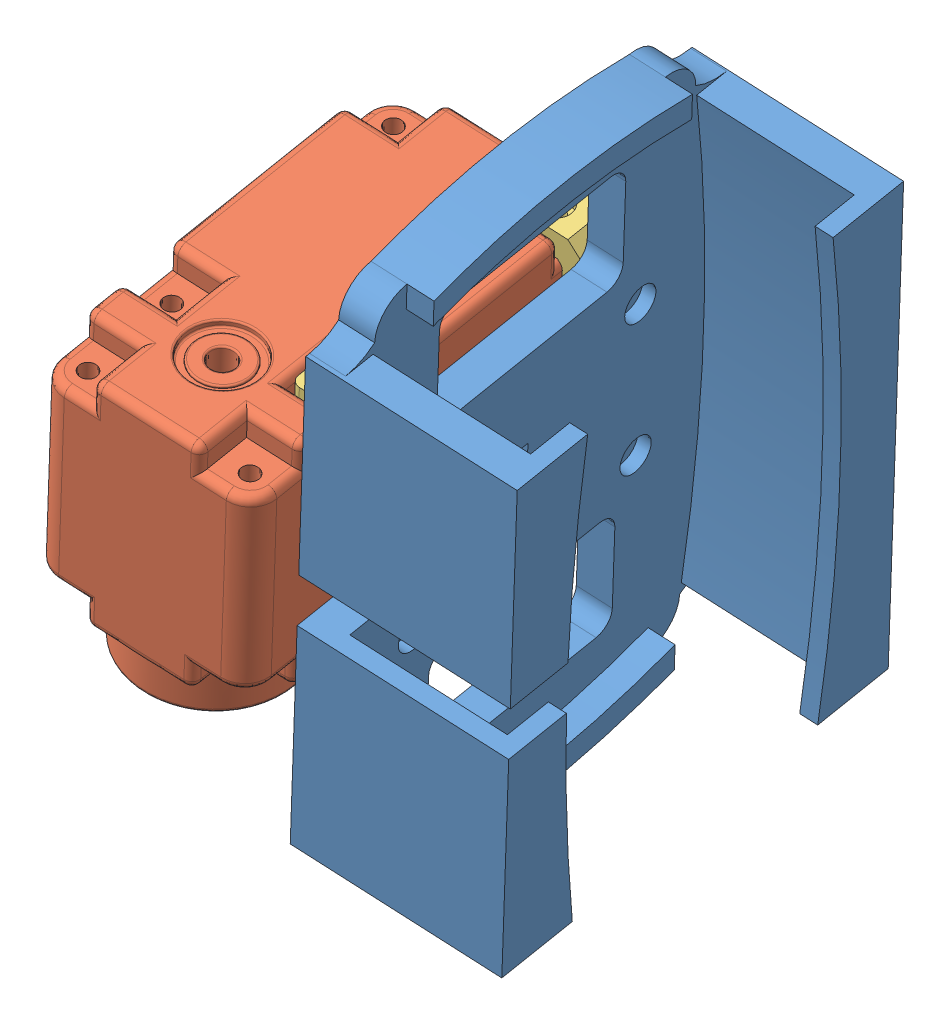
SolidWorks assembly Head_part, configuration Default. Lengths in mm.
Overall size (59.75 79.66 61.35).
6 component instances, 3 part files, 15 mates.
Components (placement in the parent):
- Cam_holder-1: Cam_holder [Default] at (91.8393 37.5422 29.7266) x (-0.138032 -0.984679 -0.106555) z (0.063253 -0.11613 0.991218) size (71.97 23.5 49.34)
- herkulex_motor-1: herkulex_motor [Default] at (79.8473 53.0849 37.7102) x (0.988406 -0.13008 -0.078314) z (-0.063253 0.11613 -0.991218) size (24 34.2 45)
- L joint-1: L joint [Default] at (86.2304 28.548 12.1828) x (0.138032 0.984679 0.106555) z (0.988406 -0.13008 -0.078314) size (8.2 5.1 8.2)
- L joint-2: L joint [Default] at (89.7278 50.6034 19.6888) x (-0.138032 -0.984679 -0.106555) z (0.988406 -0.13008 -0.078314) size (8.2 5.1 8.2)
- L joint-3: L joint [Default] at (91.5178 47.3169 47.7403) x (-0.138032 -0.984679 -0.106555) z (0.988406 -0.13008 -0.078314) size (8.2 5.1 8.2)
- L joint-5: L joint [Default] at (88.3431 24.6693 45.2895) x (-0.988406 0.13008 0.078314) z (-0.138032 -0.984679 -0.106555) size (8.2 5.1 8.2)
Mates (geometry in assembly coordinates):
- Concentric1: concentric aligned: cylinder of herkulex_motor-1 through (87.5095 54.1787 17.6766) axis (-0.138032 -0.984679 -0.106555) radius 1; cylinder of L joint-1 through (83.6999 27.0016 14.7357) axis (-0.138032 -0.984679 -0.106555) radius 1.7
- Coincident1: coincident anti-aligned: plane of herkulex_motor-1 through (76.2585 27.4832 34.9398) normal (-0.138032 -0.984679 -0.106555); plane of L joint-1 through (86.553 27.9557 17.238) normal (0.138032 0.984679 0.106555)
- Concentric2: concentric aligned: circle of herkulex_motor-1; circle of L joint-2
- Coincident2: coincident anti-aligned: plane of herkulex_motor-1 through (79.4332 50.1309 37.3906) normal (0.138032 0.984679 0.106555); plane of L joint-2 through (89.4052 51.1956 14.6336) normal (-0.138032 -0.984679 -0.106555)
- Concentric3: concentric anti-aligned: cylinder of herkulex_motor-1 through (89.2996 50.8922 45.7281) axis (-0.138032 -0.984679 -0.106555) radius 1; cylinder of L joint-3 through (89.1064 49.5137 45.5789) axis (0.138032 0.984679 0.106555) radius 1.7
- Coincident3: coincident anti-aligned: plane of herkulex_motor-1 through (79.4332 50.1309 37.3906) normal (0.138032 0.984679 0.106555); plane of L joint-3 through (91.1952 47.9091 42.6851) normal (-0.138032 -0.984679 -0.106555)
- Concentric5: concentric anti-aligned: cylinder of herkulex_motor-1 through (89.2996 50.8922 45.7281) axis (-0.138032 -0.984679 -0.106555) radius 1; cylinder of L joint-5 through (85.0068 20.2687 42.4142) axis (0.138032 0.984679 0.106555) radius 1
- Coincident4: coincident anti-aligned: plane of herkulex_motor-1 through (76.2585 27.4832 34.9398) normal (-0.138032 -0.984679 -0.106555); plane of L joint-5 through (88.0205 25.2615 40.2343) normal (0.138032 0.984679 0.106555)
- Parallel1: parallel aligned: plane of herkulex_motor-1 through (62.2843 26.7337 13.0444) normal (-0.063253 0.11613 -0.991218); plane of L joint-1 through (86.2304 28.548 12.1828) normal (-0.063253 0.11613 -0.991218)
- Parallel2: parallel aligned: plane of herkulex_motor-1 through (62.2843 26.7337 13.0444) normal (-0.063253 0.11613 -0.991218); plane of L joint-2 through (89.4052 51.1956 14.6336) normal (-0.063253 0.11613 -0.991218)
- Parallel3: parallel aligned: plane of herkulex_motor-1 through (62.2843 26.7337 13.0444) normal (-0.063253 0.11613 -0.991218); plane of L joint-5 through (88.0205 25.2615 40.2343) normal (-0.063253 0.11613 -0.991218)
- Parallel4: parallel aligned: plane of herkulex_motor-1 through (62.2843 26.7337 13.0444) normal (-0.063253 0.11613 -0.991218); plane of L joint-3 through (91.1952 47.9091 42.6851) normal (-0.063253 0.11613 -0.991218)
- Concentric6: concentric anti-aligned: cylinder of Cam_holder-1 through (109.4709 45.7728 15.2904) axis (0.988406 -0.13008 -0.078314) radius 1; cylinder of L joint-2 through (94.2622 47.7744 16.4954) axis (-0.988406 0.13008 0.078314) radius 1
- Concentric7: concentric anti-aligned: cylinder of Cam_holder-1 through (83.7716 31.1038 15.2118) axis (0.988406 -0.13008 -0.078314) radius 1; cylinder of L joint-1 through (91.7777 30.0502 14.5774) axis (-0.988406 0.13008 0.078314) radius 1
- Coincident9: coincident anti-aligned: plane of Cam_holder-1 through (90.389 39.9918 7.3535) normal (-0.988406 0.13008 0.078314); plane of L joint-3 through (94.5745 50.4729 42.7698) normal (0.988406 -0.13008 -0.078314)
